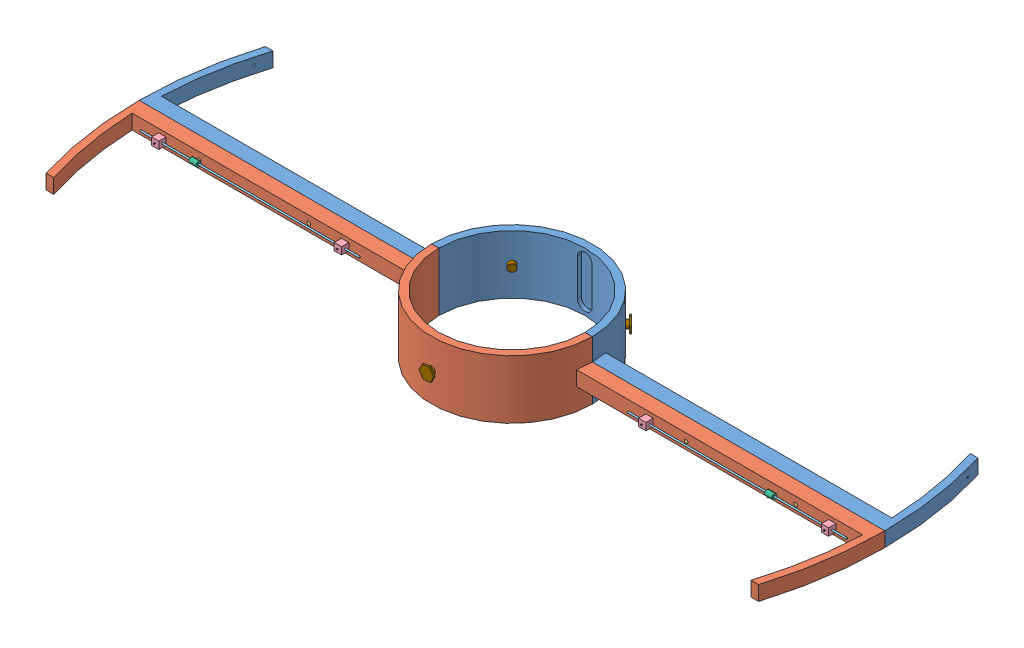
SolidWorks assembly Assemhand, configuration Default. Lengths in mm.
Overall size (1020 80 300).
23 component instances, 9 part files, 46 mates.
Components (placement in the parent):
- partabove-1: partabove [Default] at (288.0087 569.123 834.6716) size (1020 80 150)
- partbelow-1: partbelow [Default] at (288.0087 649.123 834.6716) x (1 0 0) z (0 0 -1) size (1020 80 150)
- screws-1: screws [Default] at (29.8422 609.123 812.6716) x (1 0 0) z (0 -1 0) size (6.93 42 8)
- screws-2: screws [Default] at (-120.1578 609.123 812.6716) x (1 0 0) z (0 -1 0) size (6.93 42 8)
- screws-3: screws [Default] at (696.1752 609.123 812.6716) x (1 0 0) z (0 -1 0) size (6.93 42 8)
- screws-4: screws [Default] at (546.1752 609.123 812.6716) x (1 0 0) z (0 -1 0) size (6.93 42 8)
- atta-1: atta [Default] at (-160.5096 630.9138 864.6716) x (1 0 0) z (0 1 0) size (10 15 10)
- atta-2: atta [Default] at (89.4904 630.9138 864.6716) x (1 0 0) z (0 1 0) size (10 15 10)
- atta-3: atta [Default] at (505.8234 630.9138 864.6716) x (1 0 0) z (0 1 0) size (10 15 10)
- atta-4: atta [Default] at (755.8234 630.9138 864.6716) x (1 0 0) z (0 1 0) size (10 15 10)
- bar-1: bar [Default] at (104.8422 609.123 859.6716) x (0 -0.106264 -0.994338) z (0 0.994338 -0.106264) size (2 300 2)
- bar-2: bar [Default] at (771.1752 609.123 859.6716) x (0 1 0) z (0 0 1) size (2 300 2)
- balance mass-1: balance mass [Default] at (-125.6252 609.123 859.6716) x (0 -0.998595 0.052983) z (0 0.052983 0.998595) size (7 10 7)
- balance mass-2: balance mass [Default] at (661.8728 609.123 859.6716) x (0 -0.951313 -0.308225) z (0 -0.308225 0.951313) size (7 10 7)
- screws-mass2-1: screws-mass2 [Default] at (-120.6252 609.3614 864.1653) x (1 0 0) z (0 0.998595 -0.052983) size (1.73 3.5 2)
- screws-mass2-2: screws-mass2 [Default] at (666.8728 607.736 863.9525) x (0.876892 0.457285 0.14816) z (-0.480688 0.834199 0.27028) size (1.73 3.5 2)
- screws-mass-3: screws-mass [Default] at (746.1752 609.123 866.1716) x (0.995726 -0.092361 0) z (0.092361 0.995726 0) size (1.73 5.5 2)
- screws-mass-4: screws-mass [Default] at (496.1752 609.123 866.1716) x (1 0 0) z (0 1 0) size (1.73 5.5 2)
- screws-mass-5: screws-mass [Default] at (79.8422 609.123 866.1716) x (1 0 0) z (0 1 0) size (1.73 5.5 2)
- screws-mass-6: screws-mass [Default] at (-170.1578 609.123 866.1716) x (1 0 0) z (0 1 0) size (1.73 5.5 2)
- SCREWW-1: SCREWW [Default] at (221.8142 609.123 768.4771) x (-0.046973 0.997791 0.046973) z (-0.705545 -0.06643 0.705545) size (17.32 22 20)
- SCREWW-2: SCREWW [Default] at (354.2278 609.123 768.4525) x (0.282022 -0.917021 0.282022) z (0.648432 0.398839 0.648432) size (17.32 22 20)
- SCREWW-3: SCREWW [Default] at (288.0087 609.123 929.791) x (0.904022 -0.427486 0) z (-0.427486 -0.904022 0) size (17.32 22 20)
Mates (geometry in assembly coordinates):
- Coincident1: coincident anti-aligned: plane of partabove-1 through (178.0087 649.123 834.6716) normal (0 0 1); plane of partbelow-1 through (178.0087 569.123 834.6716) normal (0 0 -1)
- Coincident2: coincident aligned: plane of partabove-1 through (-211.9913 619.123 834.6716) normal (0 1 0); plane of partbelow-1 through (-211.9913 619.123 834.6716) normal (0 1 0)
- Concentric1: concentric anti-aligned: cylinder of partabove-1 through (288.0087 599.123 834.6716) axis (0 1 0) radius 510; cylinder of partbelow-1 through (288.0087 619.123 834.6716) axis (0 -1 0) radius 510
- Concentric2: concentric aligned: cylinder of partabove-1 through (696.1752 609.123 834.6716) axis (0 0 -1) radius 2.5; cylinder of screws-3 through (696.1752 609.123 854.6716) axis (0 0 -1) radius 2.5
- Concentric3: concentric aligned: cylinder of partabove-1 through (546.1752 609.123 834.6716) axis (0 0 -1) radius 2.5; cylinder of screws-4 through (546.1752 609.123 854.6716) axis (0 0 -1) radius 2.5
- Concentric4: concentric aligned: cylinder of partabove-1 through (29.8422 609.123 834.6716) axis (0 0 -1) radius 2.5; cylinder of screws-1 through (29.8422 609.123 854.6716) axis (0 0 -1) radius 2.5
- Concentric5: concentric aligned: cylinder of partabove-1 through (-120.1578 609.123 834.6716) axis (0 0 -1) radius 2.5; cylinder of screws-2 through (-120.1578 609.123 854.6716) axis (0 0 -1) radius 2.5
- Coincident3: coincident anti-aligned: plane of partabove-1 through (-211.9913 599.123 814.6716) normal (0 0 -1); plane of screws-2 through (-120.1578 609.123 814.6716) normal (0 0 1)
- Coincident4: coincident anti-aligned: plane of partabove-1 through (-211.9913 599.123 814.6716) normal (0 0 -1); plane of screws-1 through (29.8422 609.123 814.6716) normal (0 0 1)
- Coincident5: coincident anti-aligned: plane of partabove-1 through (788.0087 569.123 814.6716) normal (0 0 -1); plane of screws-4 through (546.1752 609.123 814.6716) normal (0 0 1)
- Coincident6: coincident anti-aligned: plane of partabove-1 through (788.0087 569.123 814.6716) normal (0 0 -1); plane of screws-3 through (696.1752 609.123 814.6716) normal (0 0 1)
- Concentric6: concentric aligned: cylinder of partbelow-1 through (-170.1578 609.123 834.6716) axis (0 0 1) radius 2.5; cylinder of atta-1 through (-170.1578 609.123 849.6716) axis (0 0 1) radius 2.5
- Coincident7: coincident anti-aligned: plane of partbelow-1 through (-211.9913 619.123 854.6716) normal (0 0 1); plane of atta-1 through (-160.5096 630.9138 854.6716) normal (0 0 -1)
- Parallel1: parallel aligned: plane of partbelow-1 through (-211.9913 599.123 834.6716) normal (0 -1 0); plane of atta-1 through (-175.1578 604.123 854.6716) normal (0 -1 0)
- Concentric7: concentric aligned: cylinder of partbelow-1 through (79.8422 609.123 834.6716) axis (0 0 1) radius 2.5; cylinder of atta-2 through (79.8422 609.123 849.6716) axis (0 0 1) radius 2.5
- Coincident9: coincident anti-aligned: plane of partbelow-1 through (-211.9913 619.123 854.6716) normal (0 0 1); plane of atta-2 through (89.4904 630.9138 854.6716) normal (0 0 -1)
- Parallel2: parallel aligned: plane of partbelow-1 through (-211.9913 599.123 834.6716) normal (0 -1 0); plane of atta-2 through (74.8422 604.123 854.6716) normal (0 -1 0)
- Concentric8: concentric aligned: cylinder of partbelow-1 through (496.1752 609.123 834.6716) axis (0 0 1) radius 2.5; cylinder of atta-3 through (496.1752 609.123 849.6716) axis (0 0 1) radius 2.5
- Coincident11: coincident anti-aligned: plane of partbelow-1 through (788.0087 649.123 854.6716) normal (0 0 1); plane of atta-3 through (505.8234 630.9138 854.6716) normal (0 0 -1)
- Parallel3: parallel aligned: plane of partbelow-1 through (788.0087 599.123 834.6716) normal (0 -1 0); plane of atta-3 through (491.1752 604.123 854.6716) normal (0 -1 0)
- Concentric9: concentric aligned: cylinder of partbelow-1 through (746.1752 609.123 834.6716) axis (0 0 1) radius 2.5; cylinder of atta-4 through (746.1752 609.123 849.6716) axis (0 0 1) radius 2.5
- Parallel4: parallel aligned: plane of partbelow-1 through (788.0087 599.123 834.6716) normal (0 -1 0); plane of atta-4 through (741.1752 604.123 854.6716) normal (0 -1 0)
- Coincident14: coincident anti-aligned: plane of partbelow-1 through (788.0087 649.123 854.6716) normal (0 0 1); plane of atta-4 through (755.8234 630.9138 854.6716) normal (0 0 -1)
- Concentric10: concentric anti-aligned: cylinder of atta-1 through (-165.1578 609.123 859.6716) axis (-1 0 0) radius 1; cylinder of bar-1 through (-195.1578 609.123 859.6716) axis (1 0 0) radius 1
- Distance1: distance = 20 mm aligned: plane of bar-1 through (-195.1578 609.123 859.6716) normal (-1 0 0); plane of atta-1 through (-175.1578 614.123 854.6716) normal (-1 0 0)
- Concentric11: concentric anti-aligned: cylinder of atta-4 through (751.1752 609.123 859.6716) axis (-1 0 0) radius 1; cylinder of bar-2 through (471.1752 609.123 859.6716) axis (1 0 0) radius 1
- Distance2: distance = 20 mm aligned: plane of atta-4 through (751.1752 614.123 854.6716) normal (1 0 0); plane of bar-2 through (771.1752 609.123 859.6716) normal (1 0 0)
- Concentric12: concentric anti-aligned: cylinder of bar-1 through (-195.1578 609.123 859.6716) axis (1 0 0) radius 1; cylinder of balance mass-1 through (-115.6252 609.123 859.6716) axis (-1 0 0) radius 1
- LimitDistance1: limit distance = 190.4674 mm anti-aligned: plane of balance mass-1 through (-115.6252 609.123 859.6716) normal (1 0 0); plane of atta-2 through (74.8422 614.123 854.6716) normal (-1 0 0)
- Concentric13: concentric anti-aligned: cylinder of bar-2 through (471.1752 609.123 859.6716) axis (1 0 0) radius 1; cylinder of balance mass-2 through (671.8728 609.123 859.6716) axis (-1 0 0) radius 1
- LimitDistance2: limit distance = 69.3025 mm anti-aligned: plane of atta-4 through (741.1752 614.123 854.6716) normal (-1 0 0); plane of balance mass-2 through (671.8728 609.123 859.6716) normal (1 0 0)
- Concentric14: concentric aligned: cylinder of balance mass-1 through (-120.6252 609.123 859.6716) axis (0 0.052983 0.998595) radius 0.5; cylinder of screws-mass2-1 through (-120.6252 609.176 860.6702) axis (0 0.052983 0.998595) radius 0.5
- Tangent1: tangent anti-aligned: cylinder of bar-1 through (-195.1578 609.123 859.6716) axis (1 0 0) radius 1; plane of screws-mass2-1 through (-120.6252 609.176 860.6702) normal (0 -0.052983 -0.998595)
- Concentric15: concentric aligned: cylinder of balance mass-2 through (666.8728 609.123 859.6716) axis (0 -0.308225 0.951313) radius 0.5; cylinder of screws-mass2-2 through (666.8728 608.8148 860.6229) axis (0 -0.308225 0.951313) radius 0.5
- Tangent2: tangent anti-aligned: cylinder of bar-2 through (471.1752 609.123 859.6716) axis (1 0 0) radius 1; plane of screws-mass2-2 through (666.8728 608.8148 860.6229) normal (0 0.308225 -0.951313)
- Concentric16: concentric aligned: cylinder of atta-4 through (746.1752 609.123 859.6716) axis (0 0 1) radius 0.5; cylinder of screws-mass-3 through (746.1752 609.123 860.6716) axis (0 0 1) radius 0.5
- Tangent3: tangent anti-aligned: cylinder of bar-2 through (471.1752 609.123 859.6716) axis (1 0 0) radius 1; plane of screws-mass-3 through (746.1752 609.123 860.6716) normal (0 0 -1)
- Concentric17: concentric aligned: cylinder of atta-1 through (-170.1578 609.123 859.6716) axis (0 0 1) radius 0.5; cylinder of screws-mass-6 through (-170.1578 609.123 860.6716) axis (0 0 1) radius 0.5
- Tangent4: tangent anti-aligned: cylinder of bar-1 through (-195.1578 609.123 859.6716) axis (1 0 0) radius 1; plane of screws-mass-6 through (-170.1578 609.123 860.6716) normal (0 0 -1)
- Concentric18: concentric aligned: cylinder of atta-2 through (79.8422 609.123 859.6716) axis (0 0 1) radius 0.5; cylinder of screws-mass-5 through (79.8422 609.123 860.6716) axis (0 0 1) radius 0.5
- Tangent5: tangent anti-aligned: cylinder of bar-1 through (-195.1578 609.123 859.6716) axis (1 0 0) radius 1; plane of screws-mass-5 through (79.8422 609.123 860.6716) normal (0 0 -1)
- Concentric19: concentric aligned: cylinder of atta-3 through (496.1752 609.123 859.6716) axis (0 0 1) radius 0.5; cylinder of screws-mass-4 through (496.1752 609.123 860.6716) axis (0 0 1) radius 0.5
- Tangent6: tangent anti-aligned: cylinder of bar-2 through (471.1752 609.123 859.6716) axis (1 0 0) radius 1; plane of screws-mass-4 through (496.1752 609.123 860.6716) normal (0 0 -1)
- Concentric20: concentric anti-aligned: cylinder of partabove-1 through (224.3691 609.123 771.032) axis (-0.707107 0 -0.707107) radius 5; cylinder of SCREWW-1 through (207.672 609.123 754.335) axis (0.707107 0 0.707107) radius 5
- Concentric21: concentric anti-aligned: cylinder of partabove-1 through (351.6483 609.123 771.032) axis (0.707107 0 -0.707107) radius 5; cylinder of SCREWW-2 through (368.3699 609.123 754.3104) axis (-0.707107 0 0.707107) radius 5
- Concentric22: concentric anti-aligned: cylinder of partbelow-1 through (288.0087 609.123 924.6716) axis (0 0 1) radius 5; cylinder of SCREWW-3 through (288.0087 609.123 949.791) axis (0 0 -1) radius 5
